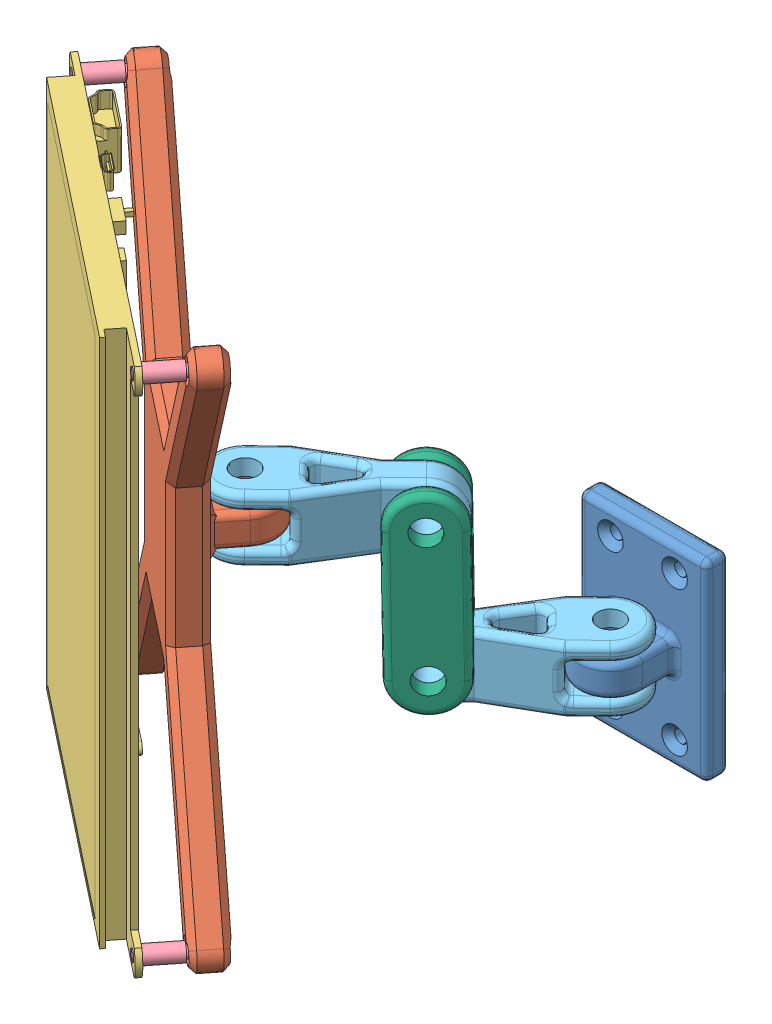
SolidWorks assembly screen arm M8, configuration Défaut. Lengths in mm.
Overall size (150.01 167 141.4).
10 component instances, 6 part files, 70 mates.
Components (placement in the parent):
- profile plate-1: profile plate [Défaut] at origin size (40 60 27)
- screen plate-1: screen plate [Défaut] at (-5.048 148.4967 124.408) x (0 -1 0) z (0.619704 0 -0.784835) size (167 124.9 30.36)
- screen.stp-1: screen.stp [Défaut] at (-59.1845 69.9967 100.2646) x (0 -1 0) z (0.784835 0 0.619704) size (166 14.1 124.15)
- entretoise-1: entretoise [Défaut] at (-95.2256 -8.5033 53.204) x (-0.000409 1 -0.000323) z (-0.619704 0 0.784835) size (5 5 14)
- entretoise-2: entretoise [Défaut] at (-5.048 148.4967 124.408) x (-0.000409 1 -0.000323) z (-0.619704 0 0.784835) size (5 5 14)
- entretoise-3: entretoise [Défaut] at (-95.2256 148.4967 53.204) x (-0.000409 1 -0.000323) z (-0.619704 0 0.784835) size (5 5 14)
- entretoise-4: entretoise [Défaut] at (-5.048 -8.5033 124.408) x (-0.000409 1 -0.000323) z (-0.619704 0 0.784835) size (5 5 14)
- screen arm male female-2: screen arm male female [Défaut] at (-15.656 20 37.7038) x (0.717178 0 -0.69689) z (0.69689 0 0.717178) size (60 20 20)
- screen arm male female-4: screen arm male female [Défaut] at (-16.0245 79.9967 38.0619) x (-0.717178 0 0.69689) z (0.69689 0 0.717178) size (60 20 20)
- screen arm female flat-1: screen arm female flat [Défaut] at (5.0845 70.1252 45.4371) x (0.009212 -0.999917 -0.008952) z (-0.69689 0 -0.717178) size (60 20 20)
Mates (geometry in assembly coordinates):
- Coïncidente1: coincident aligned: plane of profile plate-1 through (0 0 0) normal (0 0 1)
- Coïncidente2: coincident aligned: plane of profile plate-1 through (0 0 0) normal (0 1 0)
- Coïncidente3: coincident aligned: plane of profile plate-1 through (0 0 0) normal (1 0 0)
- Coïncidente4: coincident anti-aligned: plane of screen plate-1 through (-5.048 -8.5033 124.408) normal (-0.619704 0 0.784835); plane of entretoise-1 through (-95.2256 -8.5033 53.204) normal (0.619704 0 -0.784835)
- Coaxiale1: concentric aligned: cylinder of screen plate-1 through (-89.0285 -8.5033 45.3556) axis (-0.619704 0 0.784835) radius 1.75; cylinder of entretoise-1 through (-93.9862 -8.5033 51.6343) axis (-0.619704 0 0.784835) radius 1.65
- Coïncidente6: coincident anti-aligned: plane of screen plate-1 through (-5.048 -8.5033 124.408) normal (-0.619704 0 0.784835); plane of entretoise-3 through (-95.2256 148.4967 53.204) normal (0.619704 0 -0.784835)
- Coïncidente7: coincident anti-aligned: plane of screen plate-1 through (-5.048 -8.5033 124.408) normal (-0.619704 0 0.784835); plane of entretoise-2 through (-5.048 148.4967 124.408) normal (0.619704 0 -0.784835)
- Coïncidente8: coincident anti-aligned: plane of screen plate-1 through (-5.048 -8.5033 124.408) normal (-0.619704 0 0.784835); plane of entretoise-4 through (-5.048 -8.5033 124.408) normal (0.619704 0 -0.784835)
- Coaxiale2: concentric aligned: cylinder of screen plate-1 through (-89.0285 148.4967 45.3556) axis (-0.619704 0 0.784835) radius 1.75; cylinder of entretoise-3 through (-93.9862 148.4967 51.6343) axis (-0.619704 0 0.784835) radius 1.65
- Coaxiale3: concentric aligned: cylinder of screen plate-1 through (1.149 -8.5033 116.5597) axis (-0.619704 0 0.784835) radius 1.75; cylinder of entretoise-4 through (-3.8086 -8.5033 122.8383) axis (-0.619704 0 0.784835) radius 1.65
- Coaxiale4: concentric aligned: cylinder of screen plate-1 through (1.149 148.4967 116.5597) axis (-0.619704 0 0.784835) radius 1.75; cylinder of entretoise-2 through (-3.8086 148.4967 122.8383) axis (-0.619704 0 0.784835) radius 1.65
- Coaxiale10: concentric anti-aligned: cylinder of profile plate-1 through (25 30 20) axis (-1 0 0) radius 5; cylinder of vis-1 through (20 34.0105 20) axis (0 -1 0) radius 5
- Coïncidente13: coincident anti-aligned: plane of screen.stp-1 through (-56.3338 152.4967 96.6544) normal (0.619704 0 -0.784835); plane of entretoise-3 through (-101.4226 148.4967 61.0523) normal (-0.619704 0 0.784835)
- AngleLimite1: limit planar angle = 4.712389 rad anti-aligned: plane of profile plate-1 through (0 30 0) normal (0 -1 0); plane of screen arm-1 through (59.4507 20 26.6064) normal (0.16516 0 -0.986267)
- Coaxiale13: concentric anti-aligned: cylinder of screen plate-1 through (-37.7427 64.9967 73.1093) axis (0 1 0) radius 4; cylinder of screen arm-2 through (17.0406 29.413 120.5954) axis (0.989262 -0.035848 0.141688) radius 5
- Coïncidente15: coincident anti-aligned: plane of screen plate-1 through (-37.7427 64.9967 73.1093) normal (0 -1 0); plane of screen arm-2 through (31.0787 40.1848 131.1738) normal (-0.989262 0.035848 -0.141688)
- Coaxiale15: concentric: cylinder of screen arm female-1 through (61.1023 30 16.7437) axis (-0.16516 0 0.986267) radius 5; cylinder of screen arm male female-1 through (57.7991 30 36.469) axis (0.16516 0 -0.986267) radius 5
- Coïncidente17: coincident: plane of screen arm female-1 through (68.4875 40 33.1893) normal (0.16516 0 -0.986267); plane of screen arm male female-1 through (54.3776 43.4705 30.8265) normal (0.16516 0 -0.986267)
- Coaxiale16: concentric: cylinder of screen arm female-3 through (89.9972 2.7834 31.7217) axis (0.451911 0.888847 0.075677) radius 5; cylinder of screen arm male female-1 through (99.0354 20.5603 33.2352) axis (-0.451911 -0.888847 -0.075677) radius 5
- Coïncidente18: coincident anti-aligned: plane of screen arm female-3 through (84.1831 22.5447 32.5491) normal (-0.451911 -0.888847 -0.075677); plane of screen arm male female-1 through (103.8907 11.534 44.1875) normal (0.451911 0.888847 0.075677)
- AngleLimite4: limit planar angle = 3.617566 rad anti-aligned: plane of screen arm male-1 through (96.1679 11.6718 22.6158) normal (0.451911 0.888847 0.075677); plane of screen arm female-1 through (57.7991 30 36.469) normal (0 1 0)
- AngleLimite5: limit planar angle = 3.801056 rad anti-aligned: plane of screen arm male female-1 through (89.9972 2.7834 31.7217) normal (-0.16516 0 0.986267); plane of screen arm female-3 through (122.7008 6.0752 62.0472) normal (-0.66764 0.280738 0.689524)
- Coaxiale18: concentric anti-aligned: cylinder of profile plate-1 through (20 25 17) axis (0 1 0) radius 4; cylinder of screen arm female-1 through (20 40 20) axis (0 -1 0) radius 5
- Coïncidente19: coincident anti-aligned: plane of profile plate-1 through (20 35 17) normal (0 1 0); plane of screen arm female-1 through (11.7889 35 8.4857) normal (0 -1 0)
- Coaxiale19: concentric aligned: cylinder of screen plate-1 through (84.7306 -9.7399 143.4009) axis (0.66764 -0.280738 -0.689524) radius 5; cylinder of screen arm female-3 through (111.5053 -0.0059 68.1856) axis (0.66764 -0.280738 -0.689524) radius 5
- Coïncidente20: coincident anti-aligned: plane of screen plate-1 through (91.407 -12.5473 136.5057) normal (0.66764 -0.280738 -0.689524); plane of screen arm female-3 through (122.9172 -16.7267 64.289) normal (-0.66764 0.280738 0.689524)
- Coaxiale20: concentric anti-aligned: cylinder of screen arm male female-2 through (20 40 17) axis (0 -1 0) radius 4; cylinder of profile plate-1 through (20 25 17) axis (0 1 0) radius 4
- Coïncidente21: coincident anti-aligned: plane of profile plate-1 through (20 35 17) normal (0 1 0); plane of screen arm male female-2 through (34.1407 35 17.2029) normal (0 -1 0)
- Coaxiale21: concentric anti-aligned: cylinder of screen arm male female-2 through (-1.7182 30 52.0474) axis (-0.69689 0 -0.717178) radius 4; cylinder of screen arm male female-3 through (46.8924 30 51.2537) axis (0.577191 0 -0.816609) radius 5
- Coïncidente22: coincident anti-aligned: plane of screen arm male female-2 through (-12.3744 40 55.4304) normal (0.69689 0 0.717178); plane of screen arm male female-3 through (47.3842 40 33.2327) normal (-0.577191 0 0.816609)
- Coaxiale22: concentric aligned: cylinder of screen arm male female-3 through (85.3287 40 66.1753) axis (0 -1 0) radius 5; cylinder of screen arm male female-4 through (-37.7427 59.9967 73.1093) axis (0 1 0) radius 4
- Coïncidente23: coincident anti-aligned: plane of screen arm male female-3 through (87.7229 35 80.1133) normal (0 1 0); plane of screen arm male female-4 through (-37.9456 64.9967 87.25) normal (0 1 0)
- Coaxiale23: concentric anti-aligned: cylinder of screen arm male female-2 through (-1.7182 30 52.0474) axis (-0.69689 0 -0.717178) radius 4; cylinder of screen arm female-4 through (46.8924 30 51.2537) axis (0.577191 0 -0.816609) radius 5
- Coïncidente25: coincident anti-aligned: plane of screen arm male female-2 through (-19.3433 40 48.2586) normal (-0.69689 0 -0.717178); plane of screen arm female-4 through (41.6123 40 41.3988) normal (0.577191 0 -0.816609)
- Coaxiale24: concentric anti-aligned: cylinder of screen arm male female-2 through (-1.7182 30 52.0474) axis (-0.69689 0 -0.717178) radius 4; cylinder of screen arm female flat-1 through (-15.656 30 37.7038) axis (0.69689 0 0.717178) radius 4
- Coïncidente27: coincident anti-aligned: plane of screen arm male female-2 through (-19.3433 40 48.2586) normal (-0.69689 0 -0.717178); plane of screen arm female flat-1 through (-4.9083 20.1293 34.2319) normal (0.69689 0 0.717178)
- Coaxiale25: concentric anti-aligned: cylinder of screen arm male female-4 through (-2.0867 69.9967 52.4055) axis (-0.69689 0 -0.717178) radius 4; cylinder of screen arm female flat-1 through (-16.0245 69.9967 38.0619) axis (0.69689 0 0.717178) radius 4
- Coïncidente30: coincident anti-aligned: plane of screen arm male female-4 through (-5.3683 59.9967 34.6789) normal (-0.69689 0 -0.717178); plane of screen arm female flat-1 through (-5.461 80.1243 34.769) normal (0.69689 0 0.717178)
- Coaxiale26: concentric aligned: cylinder of screen plate-1 through (-37.7427 64.9967 73.1093) axis (0 1 0) radius 4; cylinder of screen arm male female-4 through (-37.7427 59.9967 73.1093) axis (0 1 0) radius 4
- Coïncidente31: coincident anti-aligned: plane of screen plate-1 through (-37.7427 64.9967 73.1093) normal (0 -1 0); plane of screen arm male female-4 through (-37.9456 64.9967 87.25) normal (0 1 0)
- AngleLimite6: limit planar angle = 3.941337 rad anti-aligned: plane of profile plate-1 through (20 0 0) normal (1 0 0); plane of screen arm male female-2 through (-8.6871 20 44.8756) normal (0.69689 0 0.717178)
- AngleLimite7: limit planar angle = 4.699543 rad aligned: plane of screen arm female flat-1 through (-2.0867 69.9967 52.4055) normal (-0.717119 -0.012845 0.696833); plane of screen arm male female-2 through (-15.656 30 37.7038) normal (0 1 0)
- AngleLimite8: limit planar angle = 1.557951 rad aligned: plane of screen arm female flat-1 through (-2.0867 69.9967 52.4055) normal (-0.717119 -0.012845 0.696833); plane of screen arm male female-4 through (-16.0245 69.9967 38.0619) normal (0 -1 0)
- AngleLimite9: limit planar angle = 3.010215 rad aligned: plane of screen arm male female-4 through (-9.0556 79.9967 45.2337) normal (0.69689 0 0.717178); plane of screen plate-1 through (-50.1368 148.4967 88.806) normal (-0.784835 0 -0.619704)
- Coaxiale27: concentric aligned: cylinder of screen.stp-1 through (-96.8069 148.4967 55.2067) axis (0.619704 0 -0.784835) radius 1.65; cylinder of entretoise-3 through (-102.662 148.4967 62.622) axis (0.619704 0 -0.784835) radius 1.65
- Coaxiale28: concentric aligned: cylinder of screen.stp-1 through (-6.6293 -8.5033 126.4107) axis (0.619704 0 -0.784835) radius 1.65; cylinder of entretoise-4 through (-12.4845 -8.5033 133.826) axis (0.619704 0 -0.784835) radius 1.65
- Coïncidente32: coincident anti-aligned: plane of screen arm male female-2 through (20 40 17) normal (0 1 0); plane of M10x25 bolt-1 through (20 40 20) normal (0 -1 0)
- Coaxiale29: concentric anti-aligned: circle of screen arm male female-2; circle of M10x25 bolt-1
- Parallèle1: parallel aligned: plane of screen arm male female-2 through (26.9689 40 24.1718) normal (0.69689 0 0.717178); plane of M10x25 bolt-1 through (29.6211 40 22.7265) normal (0.69689 0 0.717178)
- Coïncidente35: coincident anti-aligned: plane of screen arm female flat-1 through (-2.0867 69.9967 52.4055) normal (0.69689 0 0.717178); plane of M10x25 bolt-2 through (-1.7182 30 55.0474) normal (-0.69689 0 -0.717178)
- Coïncidente36: coincident anti-aligned: plane of screen arm female flat-1 through (-2.0867 69.9967 52.4055) normal (0.69689 0 0.717178); plane of M10x25 bolt-3 through (-2.0867 69.9967 55.4055) normal (-0.69689 0 -0.717178)
- Coïncidente37: coincident anti-aligned: plane of screen arm male female-4 through (-37.7427 79.9967 73.1093) normal (0 1 0); plane of M10x25 bolt-4 through (-37.7427 79.9967 76.1093) normal (0 -1 0)
- Coïncidente38: coincident aligned: circle of screen arm female flat-1; circle of M10x25 bolt-2
- Coaxiale30: concentric aligned: circle of screen arm female flat-1; circle of M10x25 bolt-3
- Coaxiale31: concentric aligned: circle of screen arm male female-4; circle of M10x25 bolt-4
- Parallèle2: parallel aligned: plane of screen arm female flat-1 through (-23.1957 69.8682 45.0302) normal (-0.717119 -0.012845 0.696833); plane of M10x25 bolt-2 through (-7.8826 24.8892 61.0374) normal (-0.717119 -0.012845 0.696833)
- Parallèle3: parallel aligned: plane of screen arm female flat-1 through (-23.1957 69.8682 45.0302) normal (-0.717119 -0.012845 0.696833); plane of M10x25 bolt-3 through (-8.2511 64.8859 61.3954) normal (-0.717119 -0.012845 0.696833)
- Parallèle4: parallel anti-aligned: plane of screen arm male female-4 through (-30.7738 59.9967 80.2811) normal (0.69689 0 0.717178); plane of M10x25 bolt-4 through (-47.3638 79.9967 73.3828) normal (-0.69689 0 -0.717178)
- Coïncidente44: coincident anti-aligned: plane of screen arm male female-2 through (20 20 17) normal (0 -1 0); plane of M10 nut-1 through (20 20 20) normal (0 1 0)
- Coïncidente45: coincident aligned: plane of M10x25 bolt-1 through (29.6211 40 22.7265) normal (0.69689 0 0.717178); plane of M10 nut-1 through (29.6211 15 22.7265) normal (0.69689 0 0.717178)
- Coïncidente46: coincident aligned: plane of M10x25 bolt-1 through (22.4494 40 29.6954) normal (-0.272649 0 0.962114); plane of M10 nut-1 through (22.4494 15 29.6954) normal (-0.272649 0 0.962114)
- Coïncidente47: coincident anti-aligned: plane of screen arm female flat-1 through (-16.0245 69.9967 38.0619) normal (-0.69689 0 -0.717178); plane of M10 nut-2 through (-15.656 30 40.7038) normal (0.69689 0 0.717178)
- Coïncidente48: coincident aligned: plane of M10x25 bolt-2 through (-7.8826 24.8892 61.0374) normal (-0.717119 -0.012845 0.696833); plane of M10 nut-2 through (-21.9125 34.8883 46.7833) normal (-0.717119 -0.012845 0.696833)
- Coïncidente49: coincident aligned: plane of M10x25 bolt-2 through (-7.9747 34.8883 61.1269) normal (-0.366537 0.859531 0.356169); plane of M10 nut-2 through (-15.7481 39.9992 40.7934) normal (-0.366537 0.859531 0.356169)
- Coïncidente50: coincident anti-aligned: plane of screen arm female flat-1 through (-16.0245 69.9967 38.0619) normal (-0.69689 0 -0.717178); plane of M10 nut-3 through (-16.0245 69.9967 41.0619) normal (0.69689 0 0.717178)
- Coïncidente51: coincident aligned: plane of M10x25 bolt-3 through (-8.2511 64.8859 61.3954) normal (-0.717119 -0.012845 0.696833); plane of M10 nut-3 through (-22.281 74.885 47.1414) normal (-0.717119 -0.012845 0.696833)
- Coïncidente52: coincident aligned: plane of M10x25 bolt-3 through (-8.3432 74.885 61.485) normal (-0.366537 0.859531 0.356169); plane of M10 nut-3 through (-16.1166 79.9959 41.1514) normal (-0.366537 0.859531 0.356169)
- Coïncidente53: coincident anti-aligned: plane of screen arm male female-4 through (-37.7427 59.9967 73.1093) normal (0 -1 0); plane of M10 nut-4 through (-37.7427 59.9967 76.1093) normal (0 1 0)
- Coïncidente54: coincident aligned: plane of M10x25 bolt-4 through (-28.1216 79.9967 78.8358) normal (0.69689 0 0.717178); plane of M10 nut-4 through (-35.2934 59.9967 85.8047) normal (0.69689 0 0.717178)
- Coïncidente55: coincident aligned: plane of M10x25 bolt-4 through (-30.5709 79.9967 69.1404) normal (0.969539 0 -0.244936); plane of M10 nut-4 through (-28.1216 59.9967 78.8358) normal (0.969539 0 -0.244936)
